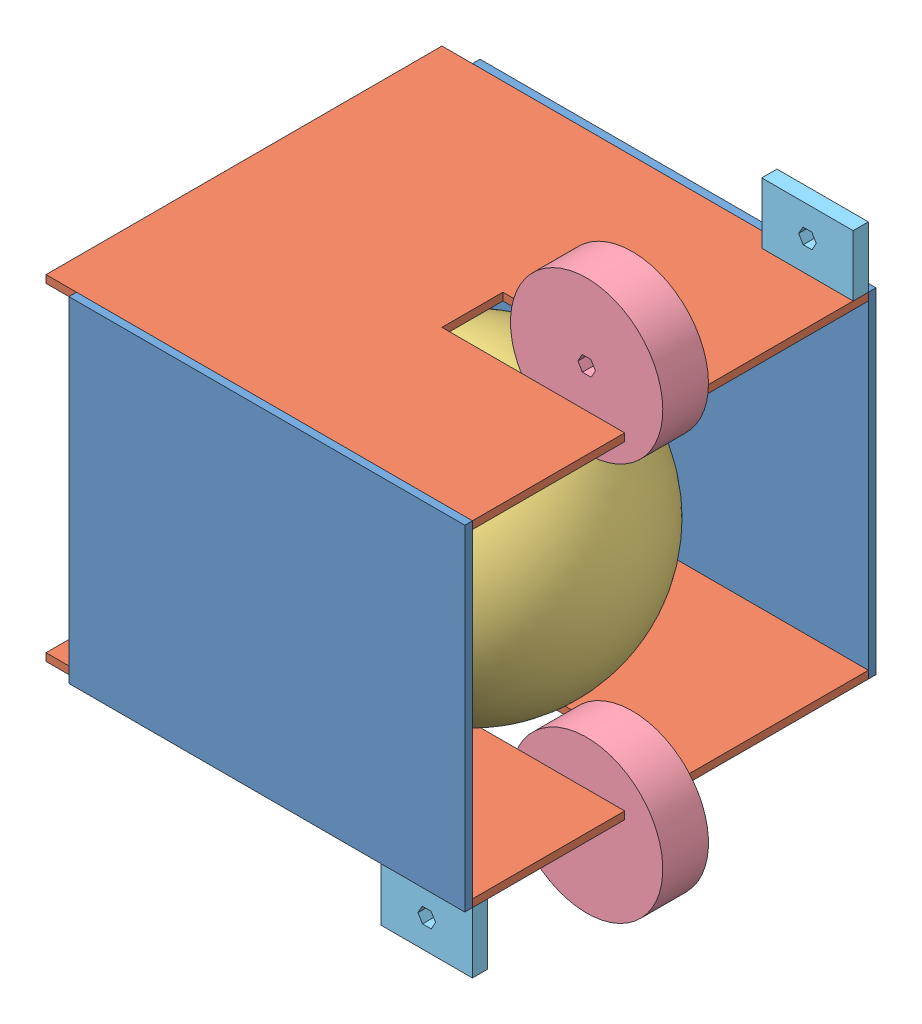
SolidWorks assembly ThrowerBox-3580300, configuration Default. Lengths in mm.
Overall size (407.23 498.87 342.9).
9 component instances, 5 part files, 20 mates.
Components (placement in the parent):
- 3580305-1: 3580305 [Default] at (-82.1979 28.1204 24.2701) size (330.2 279.4 6.35)
- 3580305-2: 3580305 [Default] at (-82.1979 28.1204 -312.2799) x (-1 0 0) z (0 0 -1) size (330.2 279.4 6.35)
- 3580306-1: 3580306 [Default] at (-94.8979 164.6454 -144.0049) x (1 0 0) z (0 1 0) size (355.6 330.2 6.35)
- 3580306-2: 3580306 [Default] at (-94.8979 -108.4046 -144.0049) x (1 0 0) z (0 1 0) size (355.6 330.2 6.35)
- ball-3580300-1: ball-3580300 [Default] at (-61.265 -98.0219 -122.7631) size (247.65 247.65 247.65)
- 3580308-1: 3580308 [Default] at (44.8021 193.9989 -131.3049) x (-0.250616 0.968087 0) z (-0.968087 -0.250616 0) size (127 38.1 127)
- 3580308-2: 3580308 [Default] at (44.8021 -137.7582 -131.3049) x (-0.735577 0.677441 0) z (0.677441 0.735577 0) size (127 38.1 127)
- box with hex-1: box with hex [Default] at (44.8021 193.2204 -302.7549) size (76.2 50.8 12.7)
- box with hex-2: box with hex [Default] at (44.8021 -136.9796 14.7451) x (-1 0 0) z (0 0 1) size (76.2 50.8 12.7)
Mates (geometry in assembly coordinates):
- Coincident14: coincident anti-aligned: plane of 3580305-1 through (-82.1979 28.1204 21.0951) normal (0 0 -1); plane of 3580306-2 through (-272.6979 -105.2296 21.0951) normal (0 0 1)
- Coincident16: coincident aligned: plane of 3580305-1 through (82.9021 -111.5796 27.4451) normal (1 0 0); plane of 3580306-2 through (82.9021 -105.2296 21.0951) normal (1 0 0)
- Coincident17: coincident anti-aligned: plane of 3580305-2 through (-82.1979 28.1204 -309.1049) normal (0 0 1); plane of 3580306-2 through (-272.6979 -105.2296 -309.1049) normal (0 0 -1)
- Coincident18: coincident anti-aligned: plane of 3580305-2 through (-82.1979 28.1204 -309.1049) normal (0 0 1); plane of 3580306-1 through (-272.6979 167.8204 -309.1049) normal (0 0 -1)
- Coincident20: coincident aligned: plane of 3580305-1 through (-247.2979 167.8204 27.4451) normal (0 1 0); plane of 3580306-1 through (-94.8979 167.8204 -144.0049) normal (0 1 0)
- Coincident21: coincident aligned: plane of 3580305-1 through (82.9021 -111.5796 27.4451) normal (1 0 0); plane of 3580306-1 through (82.9021 167.8204 21.0951) normal (1 0 0)
- Distance1: distance = 6.35 mm anti-aligned: plane of 3580308-1 through (44.8021 193.9989 -150.3549) normal (0 0 -1); plane of 3580306-2 through (82.9021 -111.5796 -156.7049) normal (0 0 1)
- Coincident22: coincident aligned: plane of 3580305-2 through (82.9021 -111.5796 -315.4549) normal (0 -1 0); plane of 3580306-2 through (-94.8979 -111.5796 -144.0049) normal (0 -1 0)
- Coincident23: coincident aligned: plane of 3580305-2 through (82.9021 167.8204 -315.4549) normal (0 1 0); plane of 3580306-1 through (-94.8979 167.8204 -144.0049) normal (0 1 0)
- Distance6: distance = 6.35 mm anti-aligned: plane of 3580308-2 through (44.8021 -137.7582 -112.2549) normal (0 0 1); plane of 3580306-2 through (82.9021 -111.5796 -105.9049) normal (0 0 -1)
- Coincident25: coincident anti-aligned: plane of 3580306-1 through (-94.8979 167.8204 -144.0049) normal (0 1 0); plane of box with hex-1 through (6.7021 167.8204 -296.4049) normal (0 -1 0)
- Coincident26: coincident aligned: plane of 3580306-1 through (82.9021 167.8204 21.0951) normal (1 0 0); plane of box with hex-1 through (82.9021 167.8204 -296.4049) normal (1 0 0)
- Coincident29: coincident anti-aligned: line of 3580306-1 through (82.9021 167.8204 -309.1049) axis (-1 0 0); line of box with hex-1 through (6.7021 167.8204 -309.1049) axis (1 0 0)
- Coincident30: coincident anti-aligned: plane of 3580306-2 through (-94.8979 -111.5796 -144.0049) normal (0 -1 0); plane of box with hex-2 through (82.9021 -111.5796 21.0951) normal (0 1 0)
- Coincident31: coincident aligned: plane of 3580306-2 through (82.9021 -105.2296 21.0951) normal (1 0 0); plane of box with hex-2 through (82.9021 -111.5796 21.0951) normal (1 0 0)
- Coincident32: coincident anti-aligned: line of 3580305-1 through (-247.2979 -111.5796 21.0951) axis (1 0 0); line of box with hex-2 through (82.9021 -111.5796 21.0951) axis (-1 0 0)
- Coincident36: coincident aligned: plane of 3580308-1 through (48.5714 187.7096 -150.3549) normal (-0.016318 0.999867 0); plane of box with hex-1 through (41.2401 187.59 -309.1049) normal (-0.016318 0.999867 0)
- Coincident38: coincident aligned: plane of 3580308-2 through (48.3642 -131.3492 -112.2549) normal (0.016318 -0.999867 0); plane of box with hex-2 through (48.3642 -131.3492 8.3951) normal (0.016318 -0.999867 0)
- Coincident39: coincident aligned: plane of 3580308-2 through (52.1335 -137.6385 -112.2549) normal (-0.857751 -0.514065 0); plane of box with hex-2 through (52.1335 -137.6385 8.3951) normal (-0.857751 -0.514065 0)
- Coincident40: coincident aligned: plane of 3580308-1 through (52.1335 194.1186 -150.3549) normal (-0.874069 0.485802 0); plane of box with hex-1 through (48.5714 187.7096 -309.1049) normal (-0.874069 0.485802 0)
